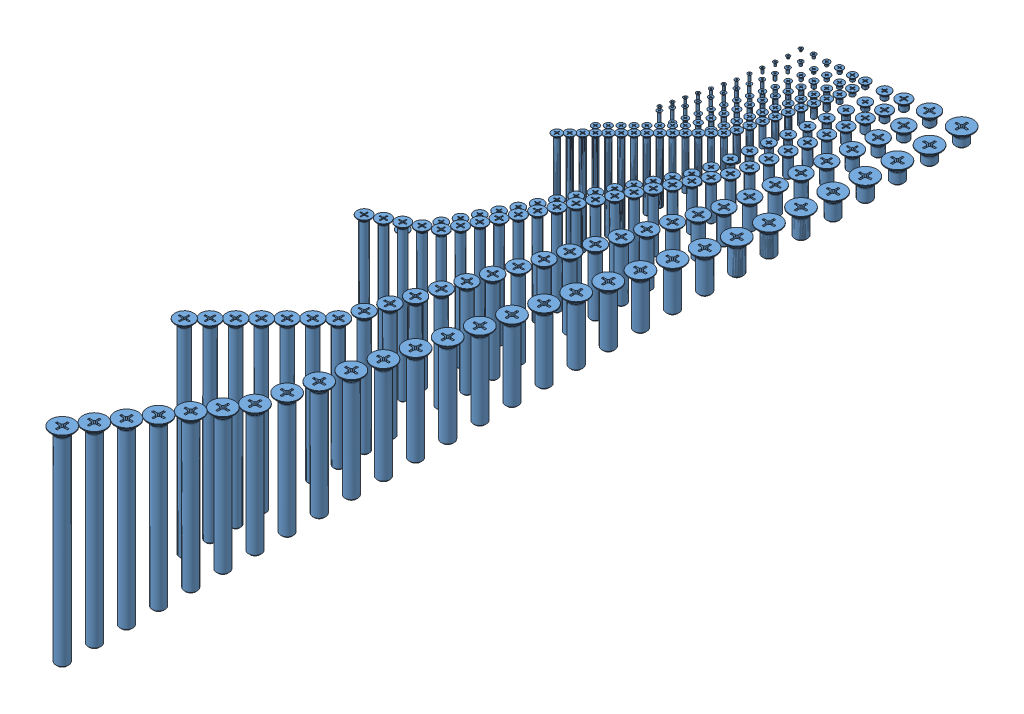
SolidWorks assembly Screw DIN 965 Ph, configuration По умолчанию. Lengths in mm.
Overall size (135.5 160 718).
219 component instances, 1 part files, 33 mates.
Components (placement in the parent):
- Screw DIN 965 Ph-829: Screw DIN 965 Ph [---M1.6---] at (-10 0 0.1076) size (3 2 3)
- Screw DIN 965 Ph-841: Screw DIN 965 Ph [---M2---] at (-0.2517 0 0) size (3.8 3 3.8)
- Screw DIN 965 Ph-842: Screw DIN 965 Ph [M2x4] at (-0.2517 0 10) size (3.8 3 3.8)
- Screw DIN 965 Ph-843: Screw DIN 965 Ph [M2x3] at (-0.2517 0 20) size (3.8 4 3.8)
- Screw DIN 965 Ph-844: Screw DIN 965 Ph [M2x5] at (-0.2517 0 30) size (3.8 5 3.8)
- Screw DIN 965 Ph-845: Screw DIN 965 Ph [M2x6] at (-0.2517 0 40) size (3.8 6 3.8)
- Screw DIN 965 Ph-846: Screw DIN 965 Ph [M2x8] at (-0.2517 0 50) size (3.8 8 3.8)
- Screw DIN 965 Ph-847: Screw DIN 965 Ph [M2х10] at (-0.2517 0 60) size (3.8 10 3.8)
- Screw DIN 965 Ph-848: Screw DIN 965 Ph [M2х12] at (-0.2517 0 70) size (3.8 12 3.8)
- Screw DIN 965 Ph-849: Screw DIN 965 Ph [M2х14] at (-0.2517 0 80) size (3.8 14 3.8)
- Screw DIN 965 Ph-850: Screw DIN 965 Ph [M2х16] at (-0.2517 0 90) size (3.8 16 3.8)
- Screw DIN 965 Ph-851: Screw DIN 965 Ph [M2х18] at (-0.2517 0 100) size (3.8 18 3.8)
- Screw DIN 965 Ph-854: Screw DIN 965 Ph [---M2.5---] at (10 0 0) x (-1 0 0) z (0 0 -1) size (4.7 3 4.7)
- Screw DIN 965 Ph-855: Screw DIN 965 Ph [M2.5x3] at (10 0 10) x (-1 0 0) z (0 0 -1) size (4.7 3 4.7)
- Screw DIN 965 Ph-856: Screw DIN 965 Ph [M2.5x4] at (10 0 20) x (-1 0 0) z (0 0 -1) size (4.7 4 4.7)
- Screw DIN 965 Ph-857: Screw DIN 965 Ph [M2.5x5] at (10 0 30) x (-1 0 0) z (0 0 -1) size (4.7 5 4.7)
- Screw DIN 965 Ph-858: Screw DIN 965 Ph [M2.5x6] at (10 0 40) x (-1 0 0) z (0 0 -1) size (4.7 6 4.7)
- Screw DIN 965 Ph-859: Screw DIN 965 Ph [M2.5x8] at (10 0 50) x (-1 0 0) z (0 0 -1) size (4.7 8 4.7)
- Screw DIN 965 Ph-860: Screw DIN 965 Ph [M2.5х10] at (10 0 60) x (-1 0 0) z (0 0 -1) size (4.7 10 4.7)
- Screw DIN 965 Ph-861: Screw DIN 965 Ph [M2.5х12] at (10 0 70) x (-1 0 0) z (0 0 -1) size (4.7 12 4.7)
- Screw DIN 965 Ph-862: Screw DIN 965 Ph [M2.5х14] at (10 0 80) x (-1 0 0) z (0 0 -1) size (4.7 14 4.7)
- Screw DIN 965 Ph-863: Screw DIN 965 Ph [M2.5х16] at (10 0 90) x (-1 0 0) z (0 0 -1) size (4.7 16 4.7)
- Screw DIN 965 Ph-864: Screw DIN 965 Ph [M2.5х18] at (10 0 100) x (-1 0 0) z (0 0 -1) size (4.7 18 4.7)
- Screw DIN 965 Ph-869: Screw DIN 965 Ph [---M3---] at (20 0 0) x (-1 0 0) z (0 0 -1) size (5.6 4 5.6)
- Screw DIN 965 Ph-870: Screw DIN 965 Ph [M3x4] at (20 0 10) x (-1 0 0) z (0 0 -1) size (5.6 4 5.6)
- Screw DIN 965 Ph-871: Screw DIN 965 Ph [M3x5] at (20 0 20) x (-1 0 0) z (0 0 -1) size (5.6 5 5.6)
- Screw DIN 965 Ph-872: Screw DIN 965 Ph [M3x6] at (20 0 30) x (-1 0 0) z (0 0 -1) size (5.6 6 5.6)
- Screw DIN 965 Ph-873: Screw DIN 965 Ph [M3x8] at (20 0 40) x (-1 0 0) z (0 0 -1) size (5.6 8 5.6)
- Screw DIN 965 Ph-874: Screw DIN 965 Ph [M3х10] at (20 0 50) x (-1 0 0) z (0 0 -1) size (5.6 10 5.6)
- Screw DIN 965 Ph-875: Screw DIN 965 Ph [M3х12] at (20 0 60) x (-1 0 0) z (0 0 -1) size (5.6 12 5.6)
- Screw DIN 965 Ph-876: Screw DIN 965 Ph [M3х14] at (20 0 70) x (-1 0 0) z (0 0 -1) size (5.6 14 5.6)
- Screw DIN 965 Ph-877: Screw DIN 965 Ph [M3х16] at (20 0 80) x (-1 0 0) z (0 0 -1) size (5.6 16 5.6)
- Screw DIN 965 Ph-878: Screw DIN 965 Ph [M3х18] at (20 0 90) x (-1 0 0) z (0 0 -1) size (5.6 18 5.6)
- Screw DIN 965 Ph-879: Screw DIN 965 Ph [M3х20] at (20 0 100) x (-1 0 0) z (0 0 -1) size (5.6 20 5.6)
- Screw DIN 965 Ph-880: Screw DIN 965 Ph [M3х22] at (20 0 110) x (-1 0 0) z (0 0 -1) size (5.6 22 5.6)
- Screw DIN 965 Ph-881: Screw DIN 965 Ph [M3х25] at (20 0 120) x (-1 0 0) z (0 0 -1) size (5.6 25 5.6)
- Screw DIN 965 Ph-882: Screw DIN 965 Ph [M3х30] at (20 0 130) x (-1 0 0) z (0 0 -1) size (5.6 30 5.6)
- Screw DIN 965 Ph-883: Screw DIN 965 Ph [M3х35] at (20 0 140) x (-1 0 0) z (0 0 -1) size (5.6 35 5.6)
- Screw DIN 965 Ph-884: Screw DIN 965 Ph [M3х40] at (20 0 150) x (-1 0 0) z (0 0 -1) size (5.6 40 5.6)
- Screw DIN 965 Ph-885: Screw DIN 965 Ph [M3х45] at (20 0 160) x (-1 0 0) z (0 0 -1) size (5.6 45 5.6)
- Screw DIN 965 Ph-886: Screw DIN 965 Ph [M3х50] at (20 0 170) x (-1 0 0) z (0 0 -1) size (5.6 50 5.6)
- Screw DIN 965 Ph-889: Screw DIN 965 Ph [---M3.5---] at (30 0 0) x (-1 0 0) z (0 0 -1) size (6.5 4 6.5)
- Screw DIN 965 Ph-890: Screw DIN 965 Ph [M3.5x4] at (30 0 10) x (-1 0 0) z (0 0 -1) size (6.5 4 6.5)
- Screw DIN 965 Ph-891: Screw DIN 965 Ph [M3.5x5] at (30 0 20) x (-1 0 0) z (0 0 -1) size (6.5 5 6.5)
- Screw DIN 965 Ph-892: Screw DIN 965 Ph [M3.5x6] at (30 0 30) x (-1 0 0) z (0 0 -1) size (6.5 6 6.5)
- Screw DIN 965 Ph-893: Screw DIN 965 Ph [M3.5x8] at (30 0 40) x (-1 0 0) z (0 0 -1) size (6.5 8 6.5)
- Screw DIN 965 Ph-894: Screw DIN 965 Ph [M3.5х10] at (30 0 50) x (-1 0 0) z (0 0 -1) size (6.5 10 6.5)
- Screw DIN 965 Ph-895: Screw DIN 965 Ph [M3.5х12] at (30 0 60) x (-1 0 0) z (0 0 -1) size (6.5 12 6.5)
- Screw DIN 965 Ph-896: Screw DIN 965 Ph [M3.5х14] at (30 0 70) x (-1 0 0) z (0 0 -1) size (6.5 14 6.5)
- Screw DIN 965 Ph-897: Screw DIN 965 Ph [M3.5х16] at (30 0 80) x (-1 0 0) z (0 0 -1) size (6.5 16 6.5)
- Screw DIN 965 Ph-898: Screw DIN 965 Ph [M3.5х18] at (30 0 90) x (-1 0 0) z (0 0 -1) size (6.5 18 6.5)
- Screw DIN 965 Ph-899: Screw DIN 965 Ph [M3.5х20] at (30 0 100) x (-1 0 0) z (0 0 -1) size (6.5 20 6.5)
- Screw DIN 965 Ph-900: Screw DIN 965 Ph [M3.5х22] at (30 0 110) x (-1 0 0) z (0 0 -1) size (6.5 22 6.5)
- Screw DIN 965 Ph-901: Screw DIN 965 Ph [M3.5х25] at (30 0 120) x (-1 0 0) z (0 0 -1) size (6.5 25 6.5)
- Screw DIN 965 Ph-902: Screw DIN 965 Ph [M3.5х30] at (30 0 130) x (-1 0 0) z (0 0 -1) size (6.5 30 6.5)
- Screw DIN 965 Ph-903: Screw DIN 965 Ph [M3.5х35] at (30 0 140) x (-1 0 0) z (0 0 -1) size (6.5 35 6.5)
- Screw DIN 965 Ph-904: Screw DIN 965 Ph [M3.5х40] at (30 0 150) x (-1 0 0) z (0 0 -1) size (6.5 40 6.5)
- Screw DIN 965 Ph-909: Screw DIN 965 Ph [---M4---] at (40 0 0) size (7.5 5 7.5)
- Screw DIN 965 Ph-910: Screw DIN 965 Ph [M4x5] at (40 0 10) size (7.5 5 7.5)
- Screw DIN 965 Ph-911: Screw DIN 965 Ph [M4x6] at (40 0 20) size (7.5 6 7.5)
- Screw DIN 965 Ph-912: Screw DIN 965 Ph [M4x8] at (40 0 30) size (7.5 8 7.5)
- Screw DIN 965 Ph-913: Screw DIN 965 Ph [М4x10] at (40 0 40) size (7.5 10 7.5)
- Screw DIN 965 Ph-914: Screw DIN 965 Ph [М4x12] at (40 0 50) size (7.5 12 7.5)
- Screw DIN 965 Ph-915: Screw DIN 965 Ph [М4x14] at (40 0 60) size (7.5 14 7.5)
- Screw DIN 965 Ph-916: Screw DIN 965 Ph [М4x16] at (40 0 70) size (7.5 16 7.5)
- Screw DIN 965 Ph-917: Screw DIN 965 Ph [М4x18] at (40 0 80) size (7.5 18 7.5)
- Screw DIN 965 Ph-918: Screw DIN 965 Ph [М4x20] at (40 0 90) size (7.5 20 7.5)
- Screw DIN 965 Ph-919: Screw DIN 965 Ph [М4x22] at (40 0 100) size (7.5 22 7.5)
- Screw DIN 965 Ph-920: Screw DIN 965 Ph [М4x25] at (40 0 110) size (7.5 25 7.5)
- Screw DIN 965 Ph-921: Screw DIN 965 Ph [М4x30] at (40 0 120) size (7.5 30 7.5)
- Screw DIN 965 Ph-922: Screw DIN 965 Ph [М4x35] at (40 0 130) size (7.5 35 7.5)
- Screw DIN 965 Ph-923: Screw DIN 965 Ph [М4x40] at (40 0 140) size (7.5 40 7.5)
- Screw DIN 965 Ph-924: Screw DIN 965 Ph [М4x45] at (40 0 150) size (7.5 45 7.5)
- Screw DIN 965 Ph-925: Screw DIN 965 Ph [М4x50] at (40 0 160) size (7.5 50 7.5)
- Screw DIN 965 Ph-926: Screw DIN 965 Ph [М4x55] at (40 0 170) size (7.5 55 7.5)
- Screw DIN 965 Ph-927: Screw DIN 965 Ph [М4x60] at (40 0 180) size (7.5 60 7.5)
- Screw DIN 965 Ph-928: Screw DIN 965 Ph [М4x65] at (40 0 190) size (7.5 65 7.5)
- Screw DIN 965 Ph-929: Screw DIN 965 Ph [М4x70] at (40 0 200) size (7.5 70 7.5)
- Screw DIN 965 Ph-934: Screw DIN 965 Ph [---M5---] at (55 0 0) x (-1 0 0) z (0 0 -1) size (9.2 6 9.2)
- Screw DIN 965 Ph-935: Screw DIN 965 Ph [M5x6] at (55 0 15) x (-1 0 0) z (0 0 -1) size (9.2 6 9.2)
- Screw DIN 965 Ph-936: Screw DIN 965 Ph [M5x8] at (55 0 30) x (-1 0 0) z (0 0 -1) size (9.2 8 9.2)
- Screw DIN 965 Ph-937: Screw DIN 965 Ph [М5x10] at (55 0 45) x (-1 0 0) z (0 0 -1) size (9.2 10 9.2)
- Screw DIN 965 Ph-938: Screw DIN 965 Ph [М5x12] at (55 0 60) x (-1 0 0) z (0 0 -1) size (9.2 12 9.2)
- Screw DIN 965 Ph-939: Screw DIN 965 Ph [М5x14] at (55 0 75) x (-1 0 0) z (0 0 -1) size (9.2 14 9.2)
- Screw DIN 965 Ph-940: Screw DIN 965 Ph [М5x16] at (55 0 90) x (-1 0 0) z (0 0 -1) size (9.2 16 9.2)
- Screw DIN 965 Ph-941: Screw DIN 965 Ph [М5x18] at (55 0 105) x (-1 0 0) z (0 0 -1) size (9.2 18 9.2)
- Screw DIN 965 Ph-942: Screw DIN 965 Ph [М5x20] at (55 0 120) x (-1 0 0) z (0 0 -1) size (9.2 20 9.2)
- Screw DIN 965 Ph-943: Screw DIN 965 Ph [М5x22] at (55 0 135) x (-1 0 0) z (0 0 -1) size (9.2 22 9.2)
- Screw DIN 965 Ph-944: Screw DIN 965 Ph [М5x25] at (55 0 150) x (-1 0 0) z (0 0 -1) size (9.2 25 9.2)
- Screw DIN 965 Ph-945: Screw DIN 965 Ph [М5x30] at (55 0 165) x (-1 0 0) z (0 0 -1) size (9.2 30 9.2)
- Screw DIN 965 Ph-946: Screw DIN 965 Ph [М5x35] at (55 0 180) x (-1 0 0) z (0 0 -1) size (9.2 35 9.2)
- Screw DIN 965 Ph-947: Screw DIN 965 Ph [М5x40] at (55 0 195) x (-1 0 0) z (0 0 -1) size (9.2 40 9.2)
- Screw DIN 965 Ph-948: Screw DIN 965 Ph [М5x45] at (55 0 210) x (-1 0 0) z (0 0 -1) size (9.2 45 9.2)
- Screw DIN 965 Ph-949: Screw DIN 965 Ph [М5x50] at (55 0 225) x (-1 0 0) z (0 0 -1) size (9.2 50 9.2)
- Screw DIN 965 Ph-950: Screw DIN 965 Ph [М5x55] at (55 0 240) x (-1 0 0) z (0 0 -1) size (9.2 55 9.2)
- Screw DIN 965 Ph-951: Screw DIN 965 Ph [М5x60] at (55 0 255) x (-1 0 0) z (0 0 -1) size (9.2 60 9.2)
- Screw DIN 965 Ph-952: Screw DIN 965 Ph [М5x65] at (55 0 270) x (-1 0 0) z (0 0 -1) size (9.2 65 9.2)
- Screw DIN 965 Ph-953: Screw DIN 965 Ph [М5x70] at (55 0 285) x (-1 0 0) z (0 0 -1) size (9.2 70 9.2)
- Screw DIN 965 Ph-954: Screw DIN 965 Ph [М5x75] at (55 0 300) x (-1 0 0) z (0 0 -1) size (9.2 75 9.2)
- Screw DIN 965 Ph-955: Screw DIN 965 Ph [М5x80] at (55 0 315) x (-1 0 0) z (0 0 -1) size (9.2 80 9.2)
- Screw DIN 965 Ph-956: Screw DIN 965 Ph [М5x85] at (55 0 330) x (-1 0 0) z (0 0 -1) size (9.2 85 9.2)
- Screw DIN 965 Ph-957: Screw DIN 965 Ph [М5x90] at (55 0 345) x (-1 0 0) z (0 0 -1) size (9.2 90 9.2)
- Screw DIN 965 Ph-958: Screw DIN 965 Ph [М5x95] at (55 0 360) x (-1 0 0) z (0 0 -1) size (9.2 95 9.2)
- Screw DIN 965 Ph-959: Screw DIN 965 Ph [М5x100] at (55 0 375) x (-1 0 0) z (0 0 -1) size (9.2 100 9.2)
- Screw DIN 965 Ph-960: Screw DIN 965 Ph [---M6---] at (70 0 0) x (-1 0 0) z (0 0 -1) size (11 8 11)
- Screw DIN 965 Ph-961: Screw DIN 965 Ph [M6x8] at (70 0 15) x (-1 0 0) z (0 0 -1) size (11 8 11)
- Screw DIN 965 Ph-962: Screw DIN 965 Ph [М6x10] at (70 0 30) x (-1 0 0) z (0 0 -1) size (11 10 11)
- Screw DIN 965 Ph-963: Screw DIN 965 Ph [М6x12] at (70 0 45) x (-1 0 0) z (0 0 -1) size (11 12 11)
- Screw DIN 965 Ph-964: Screw DIN 965 Ph [М6x14] at (70 0 60) x (-1 0 0) z (0 0 -1) size (11 14 11)
- Screw DIN 965 Ph-965: Screw DIN 965 Ph [М6x16] at (70 0 75) x (-1 0 0) z (0 0 -1) size (11 16 11)
- Screw DIN 965 Ph-966: Screw DIN 965 Ph [М6x18] at (70 0 90) x (-1 0 0) z (0 0 -1) size (11 18 11)
- Screw DIN 965 Ph-967: Screw DIN 965 Ph [М6x20] at (70 0 105) x (-1 0 0) z (0 0 -1) size (11 20 11)
- Screw DIN 965 Ph-968: Screw DIN 965 Ph [М6x22] at (70 0 120) x (-1 0 0) z (0 0 -1) size (11 22 11)
- Screw DIN 965 Ph-969: Screw DIN 965 Ph [М6x25] at (70 0 135) x (-1 0 0) z (0 0 -1) size (11 25 11)
- Screw DIN 965 Ph-970: Screw DIN 965 Ph [М6x30] at (70 0 150) x (-1 0 0) z (0 0 -1) size (11 30 11)
- Screw DIN 965 Ph-971: Screw DIN 965 Ph [М6x35] at (70 0 165) x (-1 0 0) z (0 0 -1) size (11 35 11)
- Screw DIN 965 Ph-972: Screw DIN 965 Ph [М6x40] at (70 0 180) x (-1 0 0) z (0 0 -1) size (11 40 11)
- Screw DIN 965 Ph-973: Screw DIN 965 Ph [М6x45] at (70 0 195) x (-1 0 0) z (0 0 -1) size (11 45 11)
- Screw DIN 965 Ph-974: Screw DIN 965 Ph [М6x50] at (70 0 210) x (-1 0 0) z (0 0 -1) size (11 50 11)
- Screw DIN 965 Ph-975: Screw DIN 965 Ph [М6x55] at (70 0 225) x (-1 0 0) z (0 0 -1) size (11 55 11)
- Screw DIN 965 Ph-976: Screw DIN 965 Ph [М6x60] at (70 0 240) x (-1 0 0) z (0 0 -1) size (11 60 11)
- Screw DIN 965 Ph-977: Screw DIN 965 Ph [М6x65] at (70 0 255) x (-1 0 0) z (0 0 -1) size (11 65 11)
- Screw DIN 965 Ph-978: Screw DIN 965 Ph [М6x70] at (70 0 270) x (-1 0 0) z (0 0 -1) size (11 70 11)
- Screw DIN 965 Ph-979: Screw DIN 965 Ph [М6x75] at (70 0 285) x (-1 0 0) z (0 0 -1) size (11 75 11)
- Screw DIN 965 Ph-980: Screw DIN 965 Ph [М6x80] at (70 0 300) x (-1 0 0) z (0 0 -1) size (11 80 11)
- Screw DIN 965 Ph-981: Screw DIN 965 Ph [М6x85] at (70 0 315) x (-1 0 0) z (0 0 -1) size (11 85 11)
- Screw DIN 965 Ph-982: Screw DIN 965 Ph [М6x90] at (70 0 330) x (-1 0 0) z (0 0 -1) size (11 90 11)
- Screw DIN 965 Ph-983: Screw DIN 965 Ph [М6x95] at (70 0 345) x (-1 0 0) z (0 0 -1) size (11 95 11)
- Screw DIN 965 Ph-984: Screw DIN 965 Ph [М6x100] at (70 0 360) x (-1 0 0) z (0 0 -1) size (11 100 11)
- Screw DIN 965 Ph-985: Screw DIN 965 Ph [М6x110] at (70 0 375) x (-1 0 0) z (0 0 -1) size (11 110 11)
- Screw DIN 965 Ph-986: Screw DIN 965 Ph [М6x120] at (70 0 390) x (-1 0 0) z (0 0 -1) size (11 120 11)
- Screw DIN 965 Ph-987: Screw DIN 965 Ph [М6x130] at (70 0 405) x (-1 0 0) z (0 0 -1) size (11 130 11)
- Screw DIN 965 Ph-989: Screw DIN 965 Ph [---M8---] at (90 0 0) x (-1 0 0) z (0 0 -1) size (14.5 10 14.5)
- Screw DIN 965 Ph-990: Screw DIN 965 Ph [М8x10] at (90 0 20) x (-1 0 0) z (0 0 -1) size (14.5 10 14.5)
- Screw DIN 965 Ph-991: Screw DIN 965 Ph [М8x12] at (90 0 40) x (-1 0 0) z (0 0 -1) size (14.5 12 14.5)
- Screw DIN 965 Ph-992: Screw DIN 965 Ph [М8x14] at (90 0 60) x (-1 0 0) z (0 0 -1) size (14.5 14 14.5)
- Screw DIN 965 Ph-993: Screw DIN 965 Ph [М8x16] at (90 0 80) x (-1 0 0) z (0 0 -1) size (14.5 16 14.5)
- Screw DIN 965 Ph-994: Screw DIN 965 Ph [М8x18] at (90 0 100) x (-1 0 0) z (0 0 -1) size (14.5 18 14.5)
- Screw DIN 965 Ph-995: Screw DIN 965 Ph [М8x20] at (90 0 120) x (-1 0 0) z (0 0 -1) size (14.5 20 14.5)
- Screw DIN 965 Ph-996: Screw DIN 965 Ph [М8x22] at (90 0 140) x (-1 0 0) z (0 0 -1) size (14.5 22 14.5)
- Screw DIN 965 Ph-997: Screw DIN 965 Ph [М8x25] at (90 0 160) x (-1 0 0) z (0 0 -1) size (14.5 25 14.5)
- Screw DIN 965 Ph-998: Screw DIN 965 Ph [М8x30] at (90 0 180) x (-1 0 0) z (0 0 -1) size (14.5 30 14.5)
- Screw DIN 965 Ph-999: Screw DIN 965 Ph [М8x35] at (90 0 200) x (-1 0 0) z (0 0 -1) size (14.5 35 14.5)
- Screw DIN 965 Ph-1000: Screw DIN 965 Ph [М8x40] at (90 0 220) x (-1 0 0) z (0 0 -1) size (14.5 40 14.5)
- Screw DIN 965 Ph-1001: Screw DIN 965 Ph [М8x45] at (90 0 240) x (-1 0 0) z (0 0 -1) size (14.5 45 14.5)
- Screw DIN 965 Ph-1002: Screw DIN 965 Ph [М8x50] at (90 0 260) x (-1 0 0) z (0 0 -1) size (14.5 50 14.5)
- Screw DIN 965 Ph-1003: Screw DIN 965 Ph [М8x55] at (90 0 280) x (-1 0 0) z (0 0 -1) size (14.5 55 14.5)
- Screw DIN 965 Ph-1004: Screw DIN 965 Ph [М8x60] at (90 0 300) x (-1 0 0) z (0 0 -1) size (14.5 60 14.5)
- Screw DIN 965 Ph-1005: Screw DIN 965 Ph [М8x65] at (90 0 320) x (-1 0 0) z (0 0 -1) size (14.5 65 14.5)
- Screw DIN 965 Ph-1006: Screw DIN 965 Ph [М8x70] at (90 0 340) x (-1 0 0) z (0 0 -1) size (14.5 70 14.5)
- Screw DIN 965 Ph-1007: Screw DIN 965 Ph [М8x75] at (90 0 360) x (-1 0 0) z (0 0 -1) size (14.5 75 14.5)
- Screw DIN 965 Ph-1008: Screw DIN 965 Ph [М8x80] at (90 0 380) x (-1 0 0) z (0 0 -1) size (14.5 80 14.5)
- Screw DIN 965 Ph-1009: Screw DIN 965 Ph [М8x85] at (90 0 400) x (-1 0 0) z (0 0 -1) size (14.5 85 14.5)
- Screw DIN 965 Ph-1010: Screw DIN 965 Ph [М8x90] at (90 0 420) x (-1 0 0) z (0 0 -1) size (14.5 90 14.5)
- Screw DIN 965 Ph-1011: Screw DIN 965 Ph [М8x95] at (90 0 440) x (-1 0 0) z (0 0 -1) size (14.5 95 14.5)
- Screw DIN 965 Ph-1012: Screw DIN 965 Ph [М8x100] at (90 0 460) x (-1 0 0) z (0 0 -1) size (14.5 100 14.5)
- Screw DIN 965 Ph-1013: Screw DIN 965 Ph [М8x110] at (90 0 480) x (-1 0 0) z (0 0 -1) size (14.5 110 14.5)
- Screw DIN 965 Ph-1014: Screw DIN 965 Ph [М8x120] at (90 0 500) x (-1 0 0) z (0 0 -1) size (14.5 120 14.5)
- Screw DIN 965 Ph-1015: Screw DIN 965 Ph [М8x130] at (90 0 520) x (-1 0 0) z (0 0 -1) size (14.5 130 14.5)
- Screw DIN 965 Ph-1016: Screw DIN 965 Ph [М8x140] at (90 0 540) x (-1 0 0) z (0 0 -1) size (14.5 140 14.5)
- Screw DIN 965 Ph-1017: Screw DIN 965 Ph [М8x150] at (90 0 560) x (-1 0 0) z (0 0 -1) size (14.5 150 14.5)
- Screw DIN 965 Ph-1018: Screw DIN 965 Ph [М8x160] at (90 0 580) x (-1 0 0) z (0 0 -1) size (14.5 160 14.5)
- Screw DIN 965 Ph-1019: Screw DIN 965 Ph [---M10---] at (115 0 0) x (-1 0 0) z (0 0 -1) size (18 12 18)
- Screw DIN 965 Ph-1020: Screw DIN 965 Ph [М10x12] at (115 0 25) x (-1 0 0) z (0 0 -1) size (18 12 18)
- Screw DIN 965 Ph-1021: Screw DIN 965 Ph [М10x14] at (115 0 50) x (-1 0 0) z (0 0 -1) size (18 14 18)
- Screw DIN 965 Ph-1022: Screw DIN 965 Ph [М10x16] at (115 0 75) x (-1 0 0) z (0 0 -1) size (18 16 18)
- Screw DIN 965 Ph-1023: Screw DIN 965 Ph [М10x18] at (115 0 100) x (-1 0 0) z (0 0 -1) size (18 18 18)
- Screw DIN 965 Ph-1024: Screw DIN 965 Ph [М10x20] at (115 0 125) x (-1 0 0) z (0 0 -1) size (18 20 18)
- Screw DIN 965 Ph-1025: Screw DIN 965 Ph [М10x22] at (115 0 150) x (-1 0 0) z (0 0 -1) size (18 22 18)
- Screw DIN 965 Ph-1026: Screw DIN 965 Ph [М10x25] at (115 0 175) x (-1 0 0) z (0 0 -1) size (18 25 18)
- Screw DIN 965 Ph-1027: Screw DIN 965 Ph [М10x30] at (115 0 200) x (-1 0 0) z (0 0 -1) size (18 30 18)
- Screw DIN 965 Ph-1028: Screw DIN 965 Ph [М10x35] at (115 0 225) x (-1 0 0) z (0 0 -1) size (18 35 18)
- Screw DIN 965 Ph-1029: Screw DIN 965 Ph [М10x40] at (115 0 250) x (-1 0 0) z (0 0 -1) size (18 40 18)
- Screw DIN 965 Ph-1030: Screw DIN 965 Ph [М10x45] at (115 0 275) x (-1 0 0) z (0 0 -1) size (18 45 18)
- Screw DIN 965 Ph-1031: Screw DIN 965 Ph [М10x50] at (115 0 300) x (-1 0 0) z (0 0 -1) size (18 50 18)
- Screw DIN 965 Ph-1032: Screw DIN 965 Ph [М10x55] at (115 0 325) x (-1 0 0) z (0 0 -1) size (18 55 18)
- Screw DIN 965 Ph-1033: Screw DIN 965 Ph [М10x60] at (115 0 350) x (-1 0 0) z (0 0 -1) size (18 60 18)
- Screw DIN 965 Ph-1034: Screw DIN 965 Ph [М10x65] at (115 0 375) x (-1 0 0) z (0 0 -1) size (18 65 18)
- Screw DIN 965 Ph-1035: Screw DIN 965 Ph [М10x70] at (115 0 400) x (-1 0 0) z (0 0 -1) size (18 70 18)
- Screw DIN 965 Ph-1036: Screw DIN 965 Ph [М10x75] at (115 0 425) x (-1 0 0) z (0 0 -1) size (18 75 18)
- Screw DIN 965 Ph-1037: Screw DIN 965 Ph [М10x80] at (115 0 450) x (-1 0 0) z (0 0 -1) size (18 80 18)
- Screw DIN 965 Ph-1038: Screw DIN 965 Ph [М10x85] at (115 0 475) x (-1 0 0) z (0 0 -1) size (18 85 18)
- Screw DIN 965 Ph-1039: Screw DIN 965 Ph [М10x90] at (115 0 500) x (-1 0 0) z (0 0 -1) size (18 90 18)
- Screw DIN 965 Ph-1040: Screw DIN 965 Ph [М10x95] at (115 0 525) x (-1 0 0) z (0 0 -1) size (18 95 18)
- Screw DIN 965 Ph-1041: Screw DIN 965 Ph [М10x100] at (115 0 550) x (-1 0 0) z (0 0 -1) size (18 100 18)
- Screw DIN 965 Ph-1042: Screw DIN 965 Ph [М10x110] at (115 0 575) x (-1 0 0) z (0 0 -1) size (18 110 18)
- Screw DIN 965 Ph-1043: Screw DIN 965 Ph [М10x120] at (115 0 600) x (-1 0 0) z (0 0 -1) size (18 120 18)
- Screw DIN 965 Ph-1044: Screw DIN 965 Ph [М10x130] at (115 0 625) x (-1 0 0) z (0 0 -1) size (18 130 18)
- Screw DIN 965 Ph-1045: Screw DIN 965 Ph [М10x140] at (115 0 650) x (-1 0 0) z (0 0 -1) size (18 140 18)
- Screw DIN 965 Ph-1046: Screw DIN 965 Ph [М10x150] at (115 0 675) x (-1 0 0) z (0 0 -1) size (18 150 18)
- Screw DIN 965 Ph-1047: Screw DIN 965 Ph [М10x160] at (115 0 700) x (-1 0 0) z (0 0 -1) size (18 160 18)
- Screw DIN 965 Ph-887: Screw DIN 965 Ph [M3х55] at (20 0 180) x (-1 0 0) z (0 0 -1) size (5.6 55 5.6)
- Screw DIN 965 Ph-888: Screw DIN 965 Ph [M3х60] at (20 0 190) x (-1 0 0) z (0 0 -1) size (5.6 60 5.6)
- Screw DIN 965 Ph-852: Screw DIN 965 Ph [M2х22] at (-0.2517 0 110) size (3.8 22 3.8)
- Screw DIN 965 Ph-853: Screw DIN 965 Ph [M2х25] at (-0.2517 0 120) size (3.8 25 3.8)
- Screw DIN 965 Ph-830: Screw DIN 965 Ph [M1.6x2] at (-10 0 10.1076) size (3 2 3)
- Screw DIN 965 Ph-831: Screw DIN 965 Ph [M1.6x3] at (-10 0 20.1076) size (3 3 3)
- Screw DIN 965 Ph-832: Screw DIN 965 Ph [M1.6x4] at (-10 0 30.1076) size (3 4 3)
- Screw DIN 965 Ph-833: Screw DIN 965 Ph [M1.6x5] at (-10 0 40.1076) size (3 5 3)
- Screw DIN 965 Ph-834: Screw DIN 965 Ph [M1.6x6] at (-10 0 50.1076) size (3 6 3)
- Screw DIN 965 Ph-835: Screw DIN 965 Ph [M1.6x8] at (-10 0 60.1076) size (3 8 3)
- Screw DIN 965 Ph-836: Screw DIN 965 Ph [M1.6х10] at (-10 0 70.1076) size (3 10 3)
- Screw DIN 965 Ph-837: Screw DIN 965 Ph [M1.6х12] at (-10 0 80.1076) size (3 12 3)
- Screw DIN 965 Ph-838: Screw DIN 965 Ph [M1.6х14] at (-10 0 90.1076) size (3 14 3)
- Screw DIN 965 Ph-839: Screw DIN 965 Ph [M1.6х16] at (-10 0 100.1076) size (3 16 3)
- Screw DIN 965 Ph-840: Screw DIN 965 Ph [M1.6х18] at (-10 0 110.1076) size (3 18 3)
- Screw DIN 965 Ph-865: Screw DIN 965 Ph [M2.5х20] at (10 0 110) x (-1 0 0) z (0 0 -1) size (4.7 20 4.7)
- Screw DIN 965 Ph-866: Screw DIN 965 Ph [M2.5х22] at (10 0 120) x (-1 0 0) z (0 0 -1) size (4.7 22 4.7)
- Screw DIN 965 Ph-867: Screw DIN 965 Ph [M2.5х25] at (10 0 130) x (-1 0 0) z (0 0 -1) size (4.7 25 4.7)
- Screw DIN 965 Ph-905: Screw DIN 965 Ph [M3.5х45] at (30 0 160) x (-1 0 0) z (0 0 -1) size (6.5 45 6.5)
- Screw DIN 965 Ph-906: Screw DIN 965 Ph [M3.5х50] at (30 0 170) x (-1 0 0) z (0 0 -1) size (6.5 50 6.5)
- Screw DIN 965 Ph-930: Screw DIN 965 Ph [М4x75] at (40 0 210) size (7.5 75 7.5)
- Screw DIN 965 Ph-931: Screw DIN 965 Ph [М4x80] at (40 0 220) size (7.5 80 7.5)
- Screw DIN 965 Ph-932: Screw DIN 965 Ph [М4x85] at (40 0 230) size (7.5 85 7.5)
- Screw DIN 965 Ph-933: Screw DIN 965 Ph [М4x90] at (40 0 240) size (7.5 90 7.5)
- Screw DIN 965 Ph-868: Screw DIN 965 Ph [M2.5х30] at (10 0 140) x (-1 0 0) z (0 0 -1) size (4.7 30 4.7)
- Screw DIN 965 Ph-907: Screw DIN 965 Ph [M3.5х55] at (30 0 180) x (-1 0 0) z (0 0 -1) size (6.5 55 6.5)
- Screw DIN 965 Ph-908: Screw DIN 965 Ph [M3.5х60] at (30 0 190) x (-1 0 0) z (0 0 -1) size (6.5 60 6.5)
- Screw DIN 965 Ph-988: Screw DIN 965 Ph [М6x140] at (70 0 420) x (-1 0 0) z (0 0 -1) size (11 140 11)
Mates (geometry in assembly coordinates):
- Параллельность1: parallel aligned: plane of Screw DIN 965 Ph-841 through (-0.2517 0 0) normal (0 0 1)
- Совпадение1: coincident anti-aligned: plane of Screw DIN 965 Ph-841 through (-0.2517 0 0) normal (0 -1 0)
- Совпадение3: coincident aligned: plane of Screw DIN 965 Ph-841 through (-0.2517 0 0) normal (0 0 1)
- Совпадение4: coincident aligned: plane of Screw DIN 965 Ph-841 through (-0.2517 0 0) normal (0 -1 0); plane of Screw DIN 965 Ph-854 through (10 0 0) normal (0 -1 0)
- Совпадение5: coincident anti-aligned: plane of Screw DIN 965 Ph-841 through (-0.2517 0 0) normal (0 0 1); plane of Screw DIN 965 Ph-854 through (10 0 0) normal (0 0 -1)
- Расстояние1: distance = 10 mm anti-aligned: cylinder of assembly; plane of Screw DIN 965 Ph-854 through (10 0 0) normal (-1 0 0)
- Совпадение17: coincident: plane of Screw DIN 965 Ph-841 through (-0.2517 0 0) normal (0 0 1)
- Совпадение18: coincident anti-aligned: plane of Screw DIN 965 Ph-869 through (20 0 0) normal (0 0 -1)
- Расстояние2: distance = 20 mm anti-aligned: plane of Screw DIN 965 Ph-869 through (20 0 0) normal (-1 0 0)
- Совпадение20: coincident anti-aligned: plane of Screw DIN 965 Ph-889 through (30 0 0) normal (0 0 -1)
- Совпадение21: coincident aligned: plane of Screw DIN 965 Ph-869 through (20 0 0) normal (0 -1 0); plane of Screw DIN 965 Ph-854 through (10 0 0) normal (0 -1 0)
- Расстояние3: distance = 30 mm anti-aligned: plane of Screw DIN 965 Ph-889 through (30 0 0) normal (-1 0 0)
- Совпадение22: coincident aligned: plane of Screw DIN 965 Ph-909 through (40 0 0) normal (0 0 1)
- Совпадение23: coincident aligned: plane of Screw DIN 965 Ph-889 through (30 0 0) normal (0 -1 0); plane of Screw DIN 965 Ph-909 through (40 0 0) normal (0 -1 0)
- Расстояние4: distance = 10 mm anti-aligned: plane of Screw DIN 965 Ph-909 through (40 0 0) normal (1 0 0); plane of Screw DIN 965 Ph-889 through (30 0 0) normal (-1 0 0)
- Совпадение24: coincident aligned: plane of Screw DIN 965 Ph-909 through (40 0 0) normal (0 -1 0); plane of Screw DIN 965 Ph-934 through (55 0 0) normal (0 -1 0)
- Совпадение25: coincident anti-aligned: plane of Screw DIN 965 Ph-934 through (55 0 0) normal (0 0 -1)
- Расстояние5: distance = 55 mm anti-aligned: plane of Screw DIN 965 Ph-934 through (55 0 0) normal (-1 0 0)
- Совпадение26: coincident aligned: plane of Screw DIN 965 Ph-934 through (55 0 0) normal (0 -1 0); plane of Screw DIN 965 Ph-960 through (70 0 0) normal (0 -1 0)
- Совпадение27: coincident anti-aligned: plane of Screw DIN 965 Ph-960 through (70 0 0) normal (0 0 -1)
- Расстояние6: distance = 70 mm anti-aligned: plane of Screw DIN 965 Ph-960 through (70 0 0) normal (-1 0 0)
- Совпадение29: coincident anti-aligned: plane of Screw DIN 965 Ph-989 through (90 0 0) normal (0 0 -1)
- Совпадение30: coincident aligned: plane of Screw DIN 965 Ph-960 through (70 0 0) normal (0 -1 0); plane of Screw DIN 965 Ph-989 through (90 0 0) normal (0 -1 0)
- Расстояние7: distance = 90 mm anti-aligned: plane of Screw DIN 965 Ph-989 through (90 0 0) normal (-1 0 0)
- Совпадение31: coincident anti-aligned: plane of Screw DIN 965 Ph-1019 through (115 0 0) normal (0 0 -1)
- Совпадение32: coincident aligned: plane of Screw DIN 965 Ph-989 through (90 0 0) normal (0 -1 0); plane of Screw DIN 965 Ph-1019 through (115 0 0) normal (0 -1 0)
- Расстояние8: distance = 115 mm anti-aligned: plane of Screw DIN 965 Ph-1019 through (115 0 0) normal (-1 0 0)
- Совпадение50: coincident aligned: plane of Screw DIN 965 Ph-841 through (-0.2517 0 0) normal (0 -1 0); plane of Screw DIN 965 Ph-829 through (-10 0 0.1076) normal (0 -1 0)
- Совпадение51: coincident anti-aligned: plane of Screw DIN 965 Ph-829 through (-10 0 0.1076) normal (0 -1 0)
- Совпадение52: coincident aligned: plane of Screw DIN 965 Ph-841 through (-0.2517 0 0) normal (0 -1 0); plane of Screw DIN 965 Ph-854 through (10 0 0) normal (0 -1 0)
- Совпадение53: coincident aligned: plane of Screw DIN 965 Ph-854 through (10 0 0) normal (0 -1 0); plane of Screw DIN 965 Ph-869 through (20 0 0) normal (0 -1 0)
- Расстояние15: distance = 10 mm: plane of Screw DIN 965 Ph-829 through (-10 0 0.1076) normal (1 0 0)
- Совпадение54: coincident aligned: plane of Screw DIN 965 Ph-869 through (20 0 0) normal (0 -1 0); plane of Screw DIN 965 Ph-889 through (30 0 0) normal (0 -1 0)
